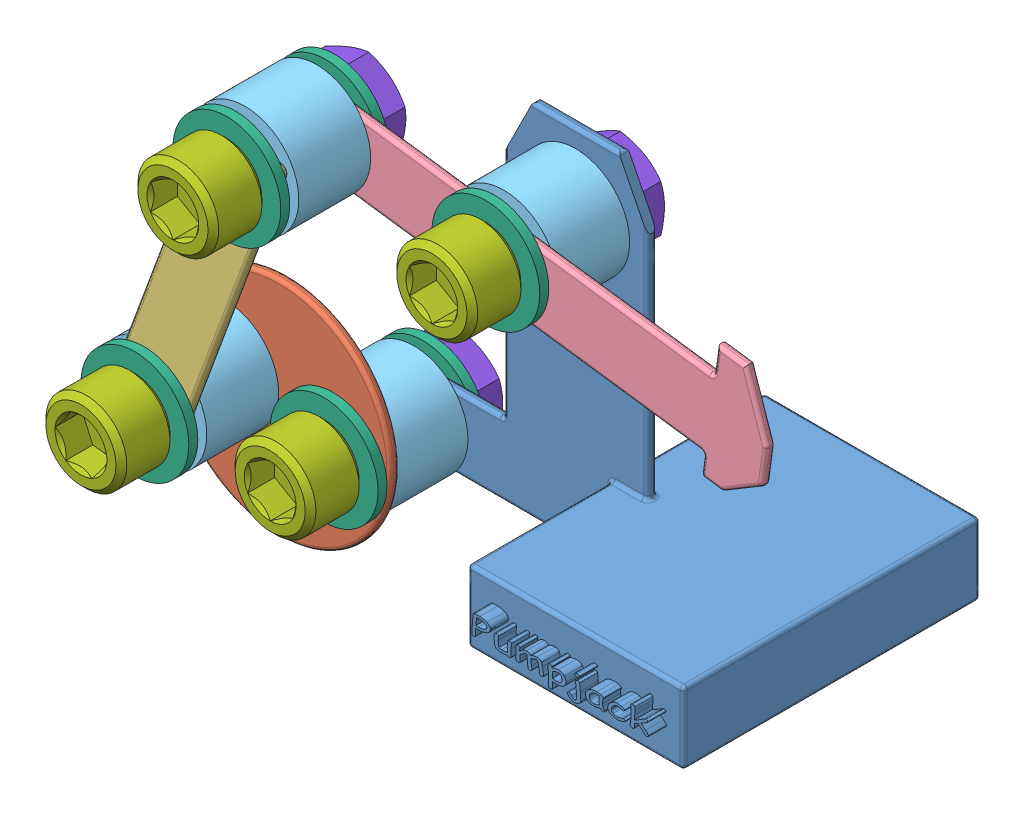
SolidWorks assembly almost, configuration Default. Lengths in mm.
Overall size (279.4 215.9 134.26).
24 component instances, 8 part files, 48 mates.
Components (placement in the parent):
- fourbarlinkage-base-1: fourbarlinkage-base [Default] at origin size (158.75 127 111.12)
- fourbarlinkage-circle-1: fourbarlinkage-circle [Default] at (-76.2857 -63.9621 28.575) x (0.234589 0.972095 0) z (0 0 1) size (78.74 78.74 3.17)
- fourbarlinkage-support-1: fourbarlinkage-support [Default] at (-37.4654 -30.622 57.15) x (0.93832 -0.345769 0) z (0 0 1) size (25.4 119.38 3.17)
- fourbarlinkage-top-1: fourbarlinkage-top [Default] at (0 20.32 28.575) x (0.99096 -0.134158 0) z (0 0 1) size (172.72 43.34 3.17)
- long spaver-1: long spaver [92320A387] at (-57.15 -68.58 15.875) size (38.1 38.1 25.4)
- 92320A599_18-8 Stainless Steel Unthreaded Spacer-1: 92320A599_18-8 Stainless Steel Unthreaded Spacer [92320A599] at (-57.15 -68.58 -1.5875) size (38.1 38.1 3.17)
- long spaver-2: long spaver [92320A387] at (0 20.32 15.875) size (38.1 38.1 25.4)
- 92320A599_18-8 Stainless Steel Unthreaded Spacer-4: 92320A599_18-8 Stainless Steel Unthreaded Spacer [92320A599] at (-57.15 -68.58 33.3375) x (0.852655 0.522475 0) z (0 0 1) size (38.1 38.1 3.17)
- 92320A599_18-8 Stainless Steel Unthreaded Spacer-5: 92320A599_18-8 Stainless Steel Unthreaded Spacer [92320A599] at (-95.4214 -59.3442 26.9875) size (38.1 38.1 3.17)
- 92320A599_18-8 Stainless Steel Unthreaded Spacer-6: 92320A599_18-8 Stainless Steel Unthreaded Spacer [92320A599] at (-62.926 28.8391 61.9125) x (-0.497469 -0.867482 0) z (0 0 1) size (38.1 38.1 3.17)
- 92320A599_18-8 Stainless Steel Unthreaded Spacer-7: 92320A599_18-8 Stainless Steel Unthreaded Spacer [92320A599] at (-95.4214 -59.3442 61.9125) x (-0.021862 -0.999761 0) z (0 0 1) size (38.1 38.1 3.17)
- 92320A599_18-8 Stainless Steel Unthreaded Spacer-8: 92320A599_18-8 Stainless Steel Unthreaded Spacer [92320A599] at (-62.926 28.8391 26.9875) x (0.919348 0.393446 0) z (0 0 1) size (38.1 38.1 3.17)
- 92320A599_18-8 Stainless Steel Unthreaded Spacer-9: 92320A599_18-8 Stainless Steel Unthreaded Spacer [92320A599] at (0 20.32 33.3375) size (38.1 38.1 3.17)
- 92320A599_18-8 Stainless Steel Unthreaded Spacer-10: 92320A599_18-8 Stainless Steel Unthreaded Spacer [92320A599] at (0 20.32 -1.5875) size (38.1 38.1 3.17)
- long spaver-3: long spaver [92320A387] at (-95.4214 -59.3442 44.45) x (-0.844104 -0.536179 0) z (0 0 1) size (38.1 38.1 25.4)
- long spaver-4: long spaver [92320A387] at (-62.926 28.8391 44.45) size (38.1 38.1 25.4)
- 91251A843_Black-Oxide Alloy Steel Socket Head Screw (1)-1: 91251A843_Black-Oxide Alloy Steel Socket Head Screw (1) [91251A843] at (-95.4214 -59.3442 47.625) x (0.102429 0.99474 0) z (0 0 1) size (28.57 28.57 71.9)
- 91251A843_Black-Oxide Alloy Steel Socket Head Screw (1)-2: 91251A843_Black-Oxide Alloy Steel Socket Head Screw (1) [91251A843] at (-57.15 -68.58 19.05) size (28.57 28.57 71.9)
- 91251A843_Black-Oxide Alloy Steel Socket Head Screw (1)-3: 91251A843_Black-Oxide Alloy Steel Socket Head Screw (1) [91251A843] at (-62.926 28.8391 47.625) size (28.57 28.57 71.9)
- 91251A843_Black-Oxide Alloy Steel Socket Head Screw (1)-4: 91251A843_Black-Oxide Alloy Steel Socket Head Screw (1) [91251A843] at (0 20.32 19.05) size (28.57 28.57 71.9)
- 91847A550_18-8 Stainless Steel Thin Hex Nut-1: 91847A550_18-8 Stainless Steel Thin Hex Nut [91847A550] at (-62.926 28.8391 20.0422) x (0.356001 -0.934485 0) z (-0.934485 -0.356001 0) size (28.57 12.69 33)
- 91847A550_18-8 Stainless Steel Thin Hex Nut-2: 91847A550_18-8 Stainless Steel Thin Hex Nut [91847A550] at (0 20.32 -8.5328) x (1 0 0) z (0 -1 0) size (28.57 12.69 33)
- 91847A550_18-8 Stainless Steel Thin Hex Nut-3: 91847A550_18-8 Stainless Steel Thin Hex Nut [91847A550] at (-95.4214 -59.3442 20.0422) x (1 0 0) z (0 -1 0) size (28.57 12.69 33)
- 91847A550_18-8 Stainless Steel Thin Hex Nut-4: 91847A550_18-8 Stainless Steel Thin Hex Nut [91847A550] at (-57.15 -68.58 -8.5328) x (1 0 0) z (0 -1 0) size (28.57 12.69 33)
Mates (geometry in assembly coordinates):
- Concentric1: concentric aligned: cylinder of fourbarlinkage-base-1 through (-57.15 -68.58 3.175) axis (0 0 -1) radius 9.525; cylinder of long spaver-1 through (-57.15 -68.58 28.575) axis (0 0 -1) radius 9.525
- Coincident1: coincident anti-aligned: plane of fourbarlinkage-base-1 through (0 0 3.175) normal (0 0 1); plane of long spaver-1 through (-57.15 -68.58 3.175) normal (0 0 -1)
- Coincident2: coincident anti-aligned: plane of fourbarlinkage-circle-1 through (-76.2857 -63.9621 28.575) normal (0 0 -1); plane of long spaver-1 through (-57.15 -68.58 28.575) normal (0 0 1)
- Concentric2: concentric aligned: cylinder of fourbarlinkage-circle-1 through (-57.15 -68.58 31.75) axis (0 0 -1) radius 9.525; cylinder of long spaver-1 through (-57.15 -68.58 28.575) axis (0 0 -1) radius 9.525
- Coincident3: coincident anti-aligned: plane of fourbarlinkage-base-1 through (0 0 0) normal (0 0 -1); plane of 92320A599_18-8 Stainless Steel Unthreaded Spacer-1 through (-57.15 -68.58 0) normal (0 0 1)
- Concentric3: concentric aligned: cylinder of fourbarlinkage-base-1 through (-57.15 -68.58 3.175) axis (0 0 -1) radius 9.525; cylinder of 92320A599_18-8 Stainless Steel Unthreaded Spacer-1 through (-57.15 -68.58 0) axis (0 0 -1) radius 9.525
- Coincident4: coincident anti-aligned: plane of fourbarlinkage-base-1 through (0 0 3.175) normal (0 0 1); plane of long spaver-2 through (0 20.32 3.175) normal (0 0 -1)
- Concentric4: concentric aligned: cylinder of fourbarlinkage-base-1 through (0 20.32 3.175) axis (0 0 -1) radius 9.525; cylinder of long spaver-2 through (0 20.32 28.575) axis (0 0 -1) radius 9.525
- Coincident5: coincident anti-aligned: plane of fourbarlinkage-top-1 through (0 20.32 28.575) normal (0 0 -1); plane of long spaver-2 through (0 20.32 28.575) normal (0 0 1)
- Concentric5: concentric anti-aligned: cylinder of fourbarlinkage-top-1 through (0 20.32 28.575) axis (0 0 1) radius 9.525; cylinder of long spaver-2 through (0 20.32 28.575) axis (0 0 -1) radius 9.525
- Coincident11: coincident anti-aligned: plane of fourbarlinkage-circle-1 through (-76.2857 -63.9621 31.75) normal (0 0 1); plane of 92320A599_18-8 Stainless Steel Unthreaded Spacer-4 through (-57.15 -68.58 31.75) normal (0 0 -1)
- Concentric10: concentric aligned: cylinder of fourbarlinkage-circle-1 through (-57.15 -68.58 31.75) axis (0 0 -1) radius 9.525; cylinder of 92320A599_18-8 Stainless Steel Unthreaded Spacer-4 through (-57.15 -68.58 34.925) axis (0 0 -1) radius 9.525
- Coincident19: coincident anti-aligned: plane of fourbarlinkage-support-1 through (-37.4654 -30.622 60.325) normal (0 0 1); plane of 92320A599_18-8 Stainless Steel Unthreaded Spacer-6 through (-62.926 28.8391 60.325) normal (0 0 -1)
- Concentric13: concentric anti-aligned: cylinder of fourbarlinkage-support-1 through (-62.926 28.8391 57.15) axis (0 0 1) radius 9.525; cylinder of 92320A599_18-8 Stainless Steel Unthreaded Spacer-6 through (-62.926 28.8391 63.5) axis (0 0 -1) radius 9.525
- Coincident20: coincident anti-aligned: plane of fourbarlinkage-top-1 through (0 20.32 28.575) normal (0 0 -1); plane of 92320A599_18-8 Stainless Steel Unthreaded Spacer-8 through (-62.926 28.8391 28.575) normal (0 0 1)
- Concentric14: concentric anti-aligned: cylinder of fourbarlinkage-top-1 through (-62.926 28.8391 28.575) axis (0 0 1) radius 9.525; cylinder of 92320A599_18-8 Stainless Steel Unthreaded Spacer-8 through (-62.926 28.8391 28.575) axis (0 0 -1) radius 9.525
- Coincident21: coincident anti-aligned: plane of fourbarlinkage-top-1 through (0 20.32 31.75) normal (0 0 1); plane of 92320A599_18-8 Stainless Steel Unthreaded Spacer-9 through (0 20.32 31.75) normal (0 0 -1)
- Concentric15: concentric anti-aligned: cylinder of fourbarlinkage-top-1 through (0 20.32 28.575) axis (0 0 1) radius 9.525; cylinder of 92320A599_18-8 Stainless Steel Unthreaded Spacer-9 through (0 20.32 34.925) axis (0 0 -1) radius 9.525
- Coincident22: coincident anti-aligned: plane of fourbarlinkage-base-1 through (0 0 0) normal (0 0 -1); plane of 92320A599_18-8 Stainless Steel Unthreaded Spacer-10 through (0 20.32 0) normal (0 0 1)
- Concentric16: concentric aligned: cylinder of fourbarlinkage-base-1 through (0 20.32 3.175) axis (0 0 -1) radius 9.525; cylinder of 92320A599_18-8 Stainless Steel Unthreaded Spacer-10 through (0 20.32 0) axis (0 0 -1) radius 9.525
- Coincident23: coincident anti-aligned: plane of fourbarlinkage-circle-1 through (-76.2857 -63.9621 31.75) normal (0 0 1); plane of long spaver-3 through (-95.4214 -59.3442 31.75) normal (0 0 -1)
- Concentric17: concentric aligned: cylinder of fourbarlinkage-circle-1 through (-95.4214 -59.3442 31.75) axis (0 0 -1) radius 9.525; cylinder of long spaver-3 through (-95.4214 -59.3442 57.15) axis (0 0 -1) radius 9.525
- Coincident24: coincident anti-aligned: plane of fourbarlinkage-support-1 through (-37.4654 -30.622 60.325) normal (0 0 1); plane of 92320A599_18-8 Stainless Steel Unthreaded Spacer-7 through (-95.4214 -59.3442 60.325) normal (0 0 -1)
- Concentric18: concentric anti-aligned: cylinder of fourbarlinkage-support-1 through (-95.4214 -59.3442 57.15) axis (0 0 1) radius 9.525; cylinder of 92320A599_18-8 Stainless Steel Unthreaded Spacer-7 through (-95.4214 -59.3442 63.5) axis (0 0 -1) radius 9.525
- Coincident25: coincident anti-aligned: plane of fourbarlinkage-support-1 through (-37.4654 -30.622 57.15) normal (0 0 -1); plane of long spaver-3 through (-95.4214 -59.3442 57.15) normal (0 0 1)
- Concentric19: concentric anti-aligned: cylinder of fourbarlinkage-support-1 through (-95.4214 -59.3442 57.15) axis (0 0 1) radius 9.525; cylinder of long spaver-3 through (-95.4214 -59.3442 57.15) axis (0 0 -1) radius 9.525
- Coincident28: coincident anti-aligned: plane of fourbarlinkage-top-1 through (0 20.32 31.75) normal (0 0 1); plane of long spaver-4 through (-62.926 28.8391 31.75) normal (0 0 -1)
- Concentric20: concentric anti-aligned: cylinder of fourbarlinkage-top-1 through (-62.926 28.8391 28.575) axis (0 0 1) radius 9.525; cylinder of long spaver-4 through (-62.926 28.8391 57.15) axis (0 0 -1) radius 9.525
- Concentric21: concentric anti-aligned: cylinder of fourbarlinkage-support-1 through (-62.926 28.8391 57.15) axis (0 0 1) radius 9.525; cylinder of long spaver-4 through (-62.926 28.8391 57.15) axis (0 0 -1) radius 9.525
- Coincident31: coincident anti-aligned: plane of fourbarlinkage-circle-1 through (-76.2857 -63.9621 28.575) normal (0 0 -1); plane of 92320A599_18-8 Stainless Steel Unthreaded Spacer-5 through (-95.4214 -59.3442 28.575) normal (0 0 1)
- Concentric23: concentric aligned: cylinder of fourbarlinkage-circle-1 through (-95.4214 -59.3442 31.75) axis (0 0 -1) radius 9.525; cylinder of 92320A599_18-8 Stainless Steel Unthreaded Spacer-5 through (-95.4214 -59.3442 28.575) axis (0 0 -1) radius 9.525
- Coincident32: coincident anti-aligned: plane of 92320A599_18-8 Stainless Steel Unthreaded Spacer-7 through (-95.4214 -59.3442 63.5) normal (0 0 1); plane of 91251A843_Black-Oxide Alloy Steel Socket Head Screw (1)-1 through (-107.7387 -58.0759 63.5) normal (0 0 -1)
- Coincident33: coincident aligned: cylinder of 92320A599_18-8 Stainless Steel Unthreaded Spacer-7 through (-95.4214 -59.3442 63.5) axis (0 0 -1) radius 9.525; circle of 91251A843_Black-Oxide Alloy Steel Socket Head Screw (1)-1
- Coincident34: coincident anti-aligned: plane of 92320A599_18-8 Stainless Steel Unthreaded Spacer-6 through (-62.926 28.8391 63.5) normal (0 0 1); plane of 91251A843_Black-Oxide Alloy Steel Socket Head Screw (1)-3 through (-62.926 41.2216 63.5) normal (0 0 -1)
- Coincident35: coincident aligned: cylinder of 92320A599_18-8 Stainless Steel Unthreaded Spacer-6 through (-62.926 28.8391 63.5) axis (0 0 -1) radius 9.525; circle of 91251A843_Black-Oxide Alloy Steel Socket Head Screw (1)-3
- Coincident36: coincident anti-aligned: plane of 92320A599_18-8 Stainless Steel Unthreaded Spacer-4 through (-57.15 -68.58 34.925) normal (0 0 1); plane of 91251A843_Black-Oxide Alloy Steel Socket Head Screw (1)-2 through (-57.15 -56.1975 34.925) normal (0 0 -1)
- Concentric24: concentric aligned: cylinder of long spaver-1 through (-57.15 -68.58 28.575) axis (0 0 -1) radius 9.525; circle of 91251A843_Black-Oxide Alloy Steel Socket Head Screw (1)-2
- Coincident38: coincident anti-aligned: plane of 92320A599_18-8 Stainless Steel Unthreaded Spacer-9 through (0 20.32 34.925) normal (0 0 1); plane of 91251A843_Black-Oxide Alloy Steel Socket Head Screw (1)-4 through (0 32.7025 34.925) normal (0 0 -1)
- Coincident39: coincident anti-aligned: plane of 92320A599_18-8 Stainless Steel Unthreaded Spacer-9 through (0 20.32 34.925) normal (0 0 1); plane of 91251A843_Black-Oxide Alloy Steel Socket Head Screw (1)-4 through (0 32.7025 34.925) normal (0 0 -1)
- Concentric25: concentric aligned: cylinder of 92320A599_18-8 Stainless Steel Unthreaded Spacer-9 through (0 20.32 34.925) axis (0 0 -1) radius 9.525; circle of 91251A843_Black-Oxide Alloy Steel Socket Head Screw (1)-4
- Coincident41: coincident anti-aligned: plane of 92320A599_18-8 Stainless Steel Unthreaded Spacer-8 through (-62.926 28.8391 25.4) normal (0 0 -1); plane of 91847A550_18-8 Stainless Steel Thin Hex Nut-1 through (-60.3039 45.1271 25.4) normal (0 0 1)
- Coincident42: coincident aligned: line of 91251A843_Black-Oxide Alloy Steel Socket Head Screw (1)-3 through (-62.926 28.8391 63.5) axis (0 0 -1); line of 91847A550_18-8 Stainless Steel Thin Hex Nut-1 through (-62.926 28.8391 25.4) axis (0 0 -1)
- Coincident44: coincident anti-aligned: plane of 92320A599_18-8 Stainless Steel Unthreaded Spacer-10 through (0 20.32 -3.175) normal (0 0 -1); plane of 91847A550_18-8 Stainless Steel Thin Hex Nut-2 through (-14.2875 28.5689 -3.175) normal (0 0 1)
- Coincident45: coincident aligned: line of 91251A843_Black-Oxide Alloy Steel Socket Head Screw (1)-4 through (0 20.32 34.925) axis (0 0 -1); line of 91847A550_18-8 Stainless Steel Thin Hex Nut-2 through (0 20.32 -3.175) axis (0 0 -1)
- Coincident46: coincident anti-aligned: plane of 92320A599_18-8 Stainless Steel Unthreaded Spacer-5 through (-95.4214 -59.3442 25.4) normal (0 0 -1); plane of 91847A550_18-8 Stainless Steel Thin Hex Nut-3 through (-109.7089 -51.0953 25.4) normal (0 0 1)
- Coincident47: coincident aligned: line of 91251A843_Black-Oxide Alloy Steel Socket Head Screw (1)-1 through (-95.4214 -59.3442 14.478) axis (0 0 -1); line of 91847A550_18-8 Stainless Steel Thin Hex Nut-3 through (-95.4214 -59.3442 25.4) axis (0 0 -1)
- Coincident48: coincident anti-aligned: plane of 92320A599_18-8 Stainless Steel Unthreaded Spacer-1 through (-57.15 -68.58 -3.175) normal (0 0 -1); plane of 91847A550_18-8 Stainless Steel Thin Hex Nut-4 through (-71.4375 -60.3311 -3.175) normal (0 0 1)
- Coincident49: coincident anti-aligned: line of 91251A843_Black-Oxide Alloy Steel Socket Head Screw (1)-2 through (-57.15 -68.58 34.925) axis (0 0 -1); line of 91847A550_18-8 Stainless Steel Thin Hex Nut-4 through (-57.15 -68.58 -19.3943) axis (0 0 1)
